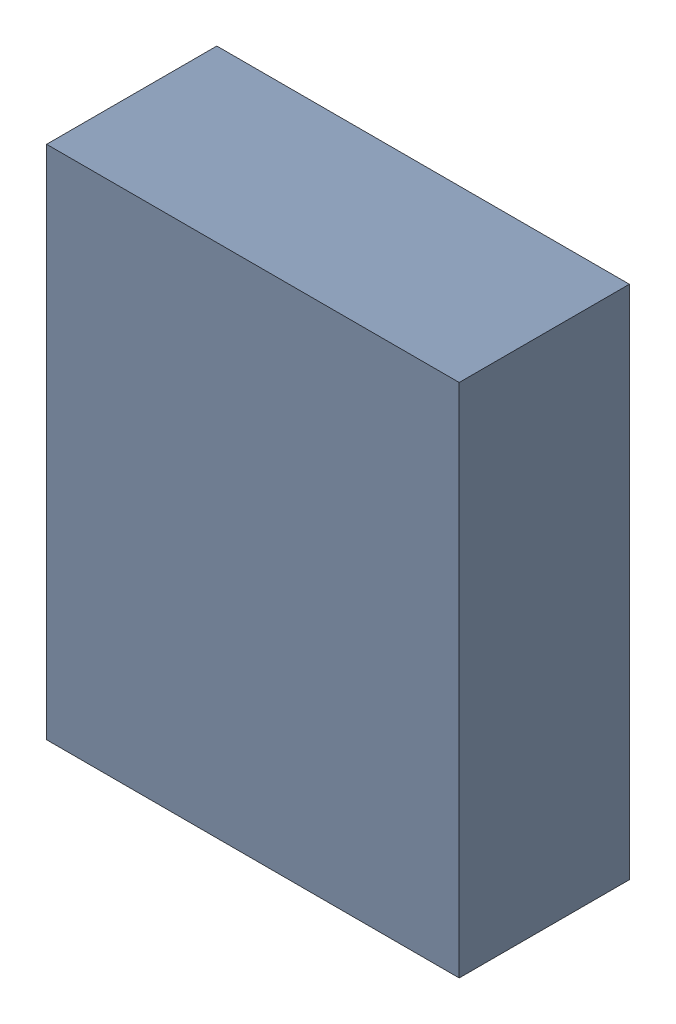
SolidWorks assembly U301_2PCB, configuration Default. Lengths in mm.
Overall size (4 5 1.65).
2 component instances, 1 part files, 0 mates.
Components (placement in the parent):
- 761608904-1: 761608904 [Default] at (150.2753 99.7181 0.1) size (4 5 1.65)
  - Extruded_35-1: Extruded_35 [Default] at origin size (4 5 1.65)
